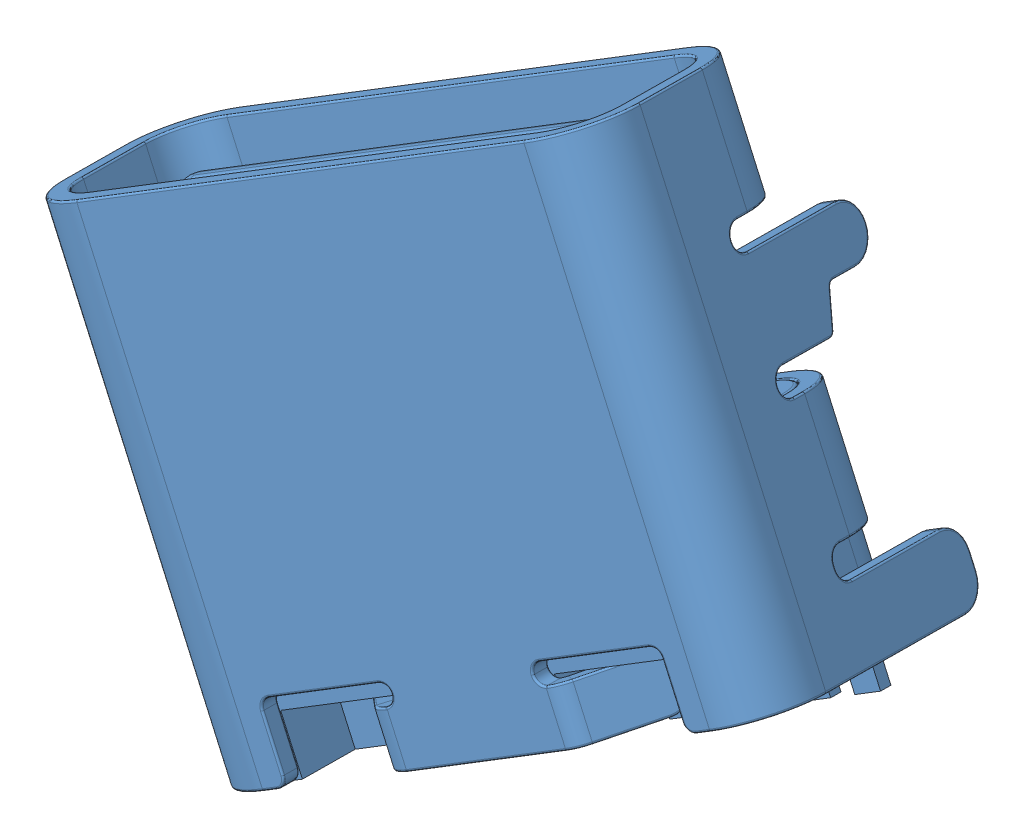
SolidWorks assembly 3D_PCB1_2023-04-23, configuration 默认. Lengths in mm.
Overall size (12.09 11.63 6.16).
4 component instances, 1 part files, 1 mates.
Components (placement in the parent):
- 3D_PCB1_2023-04-23(2)^3D_PCB1_2023-04-23-1: 3D_PCB1_2023-04-23(2)^3D_PCB1_2023-04-23 [默认] at (13.5832 -1.7809 -3.2328) x (-0.867235 -0.462011 0.185606) z (0.134238 0.142014 0.98072) size (8.94 7.9 4.1) (virtual)
  - USBC1^3D_PCB1_2023-04-23(2)_3D_PCB1_2023-04-23-1: USBC1^3D_PCB1_2023-04-23(2)_3D_PCB1_2023-04-23 [默认] at (11.557 -7.874 1.6001) size (8.94 7.9 4.1) (virtual)
    - USB-C_SMD-TYPE-C-31-M-12^USBC1_3D_PCB1_2023-04-23(2)_3D_PCB1_2023-04-23-1: USB-C_SMD-TYPE-C-31-M-12^USBC1_3D_PCB1_2023-04-23(2)_3D_PCB1_2023-04-23 [默认] at origin size (8.94 7.9 4.1) (virtual)
      - COMPOUND^USB-C_SMD-TYPE-C-31-M-12_USBC1_3D_PCB1_2023-04-23(2)_3D_PCB1_2023-04-23-1: COMPOUND^USB-C_SMD-TYPE-C-31-M-12_USBC1_3D_PCB1_2023-04-23(2)_3D_PCB1_2023-04-23 [默认] at origin size (8.94 7.9 4.1) (virtual)
Mates (geometry in assembly coordinates):
- 重合4: coincident: point of 3D_PCB1_2023-04-23(2)^3D_PCB1_2023-04-23-1/USBC1^3D_PCB1_2023-04-23(2)_3D_PCB1_2023-04-23-1
